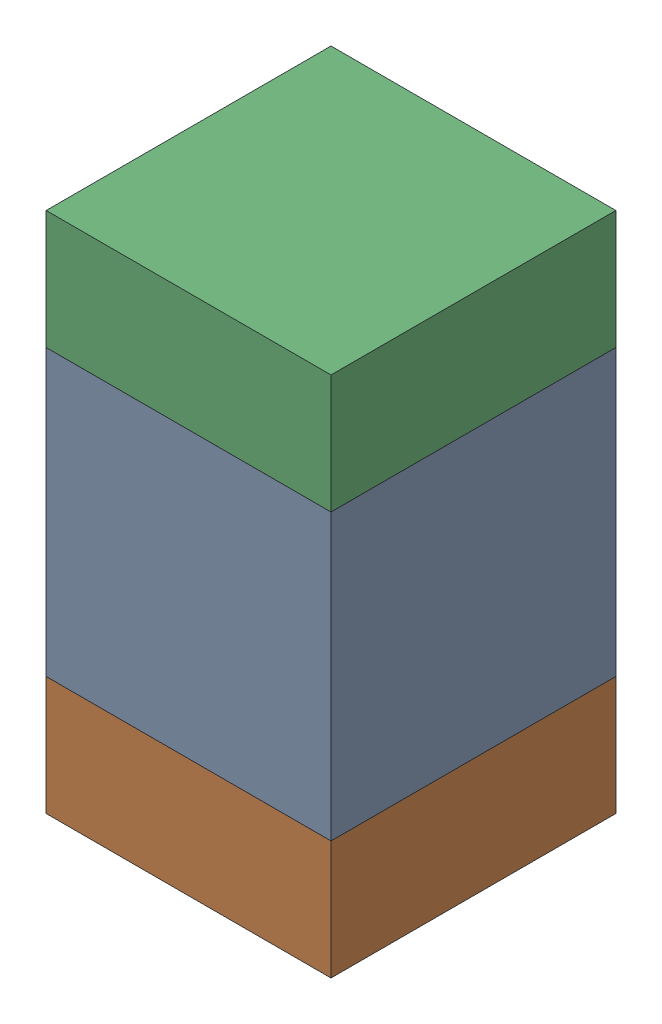
SolidWorks assembly C110_2PCB, configuration Default. Lengths in mm.
Overall size (0.6 1.1 0.6).
6 component instances, 2 part files, 0 mates.
Components (placement in the parent):
- 761606048-1: 761606048 [Default] at (116.7 92 0) size (0.6 0.6 0.6)
  - Extruded_9-1: Extruded_9 [Default] at origin size (0.6 0.6 0.6)
- 854785296-1: 854785296 [Default] at (116.7 91.575 0) size (0.6 0.25 0.6)
  - Extruded_10-1: Extruded_10 [Default] at origin size (0.6 0.25 0.6)
- 854785296-2: 854785296 [Default] at (116.7 92.425 0) size (0.6 0.25 0.6)
  - Extruded_10-1: Extruded_10 [Default] at origin size (0.6 0.25 0.6)
